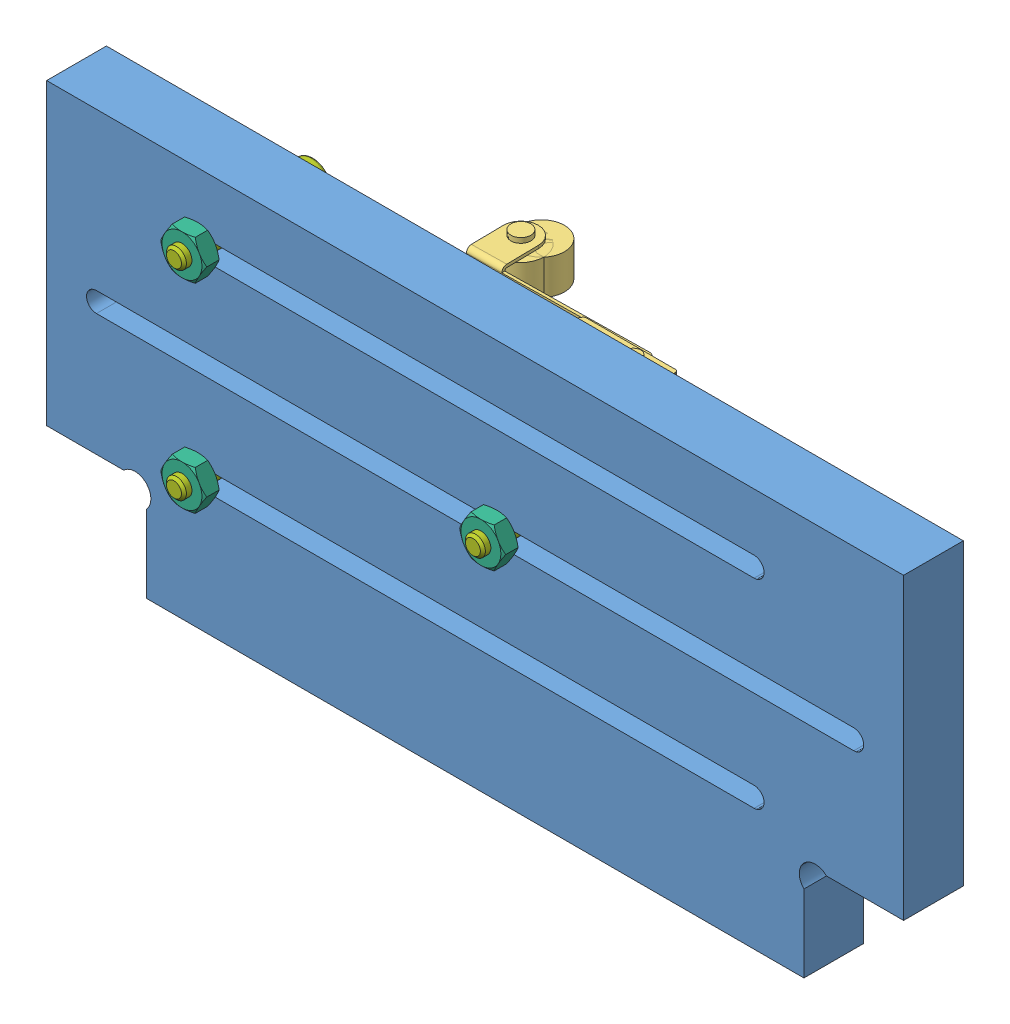
SolidWorks assembly cfc_ferme, configuration Défaut. Lengths in mm.
Overall size (86 40 30.8).
14 component instances, 7 part files, 27 mates.
Components (placement in the parent):
- cfc-platine-1: cfc-platine [Défaut] at (140.8628 -70 0) x (0 0 1) z (0 -1 0) size (6 86 40)
- Grove microswitch v1.0-1: Grove microswitch v1.0 [Défaut] at (-58.8307 23.25 -3.344) x (1 0 0) z (0 1 0) size (41.8 22.4 23.6)
  - PCB grove 20x40-1: PCB grove 20x40 [Défaut] at (-1.988 -1.344 0) size (41.8 1.6 23.6)
  - microswitch 10T85-1: microswitch 10T85 [Défaut] at (9.562 0.256 0) size (22.48 22.4 6.4)
  - Connecteur Grove (coudé CMS)-1: Connecteur Grove (coudé CMS) [Défaut] at (-21.488 0.256 0) x (0 0 -1) z (0 1 0) size (12 10 5)
- entretoise-grove-1: entretoise-grove [Défaut] at (-40.8187 23.25 -2) x (1 0.000242 0) z (0 0 1) size (4 4 2)
- entretoise-grove-2: entretoise-grove [Défaut] at (-70.8187 13.25 -2) size (4 4 2)
- entretoise-grove-3: entretoise-grove [Défaut] at (-70.8187 33.25 -2) size (4 4 2)
- ecrou-h-1: ecrou-h [6007 HU M2] at (-40.8187 23.25 7.6) x (0.866025 -0.5 0) z (-0.5 -0.866025 0) size (4 1.6 4.62)
- ecrou-h-2: ecrou-h [6007 HU M2] at (-70.8187 13.25 7.6) x (0.866025 0.5 0) z (0.5 -0.866025 0) size (4 1.6 4.62)
- ecrou-h-3: ecrou-h [6007 HU M2] at (-70.8187 33.25 7.6) x (-0.866025 0.5 0) z (0.5 0.866025 0) size (4 1.6 4.62)
- vis-chc-1: vis-chc [Vis CHC M2x12] at (-70.8187 13.25 -3.6) x (1 0 0) z (0 1 0) size (3.8 14 3.8)
- vis-chc-2: vis-chc [Vis CHC M2x12] at (-70.8187 33.25 -3.6) x (1 0 0) z (0 1 0) size (3.8 14 3.8)
- vis-chc-3: vis-chc [Vis CHC M2x12] at (-40.8187 23.25 -3.6) x (0.997694 0.067868 0) z (-0.067868 0.997694 0) size (3.8 14 3.8)
Mates (geometry in assembly coordinates):
- Coïncidente1: coincident anti-aligned: plane of cfc-platine-1 through (-8.8686 8.8686 0) normal (0 0 -1)
- Coïncidente2: coincident anti-aligned: plane of cfc-platine-1 through (-10 0 6) normal (0 -1 0)
- Coaxiale1: concentric anti-aligned: cylinder of Grove microswitch v1.0-1/PCB grove 20x40-1 through (-70.8187 33.25 -3.6) axis (0 0 1) radius 1.1; cylinder of entretoise-grove-3 through (-70.8187 33.25 0) axis (0 0 -1) radius 1.2
- Coïncidente4: coincident anti-aligned: plane of Grove microswitch v1.0-1/PCB grove 20x40-1 through (-60.8187 23.25 -2) normal (0 0 1); plane of entretoise-grove-3 through (-70.8187 33.25 -2) normal (0 0 -1)
- Coaxiale2: concentric anti-aligned: cylinder of Grove microswitch v1.0-1/PCB grove 20x40-1 through (-40.8187 23.25 -3.6) axis (0 0 1) radius 1.1; cylinder of entretoise-grove-1 through (-40.8187 23.25 0) axis (0 0 -1) radius 1.2
- Coïncidente5: coincident anti-aligned: plane of Grove microswitch v1.0-1/PCB grove 20x40-1 through (-60.8187 23.25 -2) normal (0 0 1); plane of entretoise-grove-1 through (-40.8187 23.25 -2) normal (0 0 -1)
- Coaxiale3: concentric anti-aligned: cylinder of Grove microswitch v1.0-1/PCB grove 20x40-1 through (-70.8187 13.25 -3.6) axis (0 0 1) radius 1.1; cylinder of entretoise-grove-2 through (-70.8187 13.25 0) axis (0 0 -1) radius 1.2
- Coïncidente6: coincident anti-aligned: plane of Grove microswitch v1.0-1/PCB grove 20x40-1 through (-60.8187 23.25 -2) normal (0 0 1); plane of entretoise-grove-2 through (-70.8187 13.25 -2) normal (0 0 -1)
- Coïncidente7: coincident anti-aligned: plane of cfc-platine-1 through (-8.8686 8.8686 0) normal (0 0 -1); plane of entretoise-grove-1 through (-40.8187 23.25 0) normal (0 0 1)
- Parallèle4: parallel anti-aligned: plane of cfc-platine-1 through (-86 40 6) normal (-1 0 0); plane of Grove microswitch v1.0-1/PCB grove 20x40-1 through (-40.8187 23.25 -3.6) normal (1 0 0)
- Parallèle3: parallel anti-aligned: plane of cfc-platine-1 through (-10 0 6) normal (0 -1 0); plane of Grove microswitch v1.0-1/PCB grove 20x40-1 through (-60.8187 33.25 -3.6) normal (0 1 0)
- Coaxiale4: concentric anti-aligned: cylinder of Grove microswitch v1.0-1/PCB grove 20x40-1 through (-70.8187 13.25 -3.6) axis (0 0 1) radius 1.1; cylinder of vis-chc-1 through (-70.8187 13.25 8.4) axis (0 0 -1) radius 1
- Coaxiale5: concentric anti-aligned: cylinder of Grove microswitch v1.0-1/PCB grove 20x40-1 through (-40.8187 23.25 -3.6) axis (0 0 1) radius 1.1; cylinder of vis-chc-3 through (-40.8187 23.25 8.4) axis (0 0 -1) radius 1
- Coaxiale6: concentric anti-aligned: cylinder of Grove microswitch v1.0-1/PCB grove 20x40-1 through (-70.8187 33.25 -3.6) axis (0 0 1) radius 1.1; cylinder of vis-chc-2 through (-70.8187 33.25 8.4) axis (0 0 -1) radius 1
- Coïncidente11: coincident anti-aligned: plane of Grove microswitch v1.0-1/PCB grove 20x40-1 through (-60.8187 23.25 -3.6) normal (0 0 -1); plane of vis-chc-3 through (-40.8187 23.25 -3.6) normal (0 0 1)
- Coïncidente12: coincident anti-aligned: plane of Grove microswitch v1.0-1/PCB grove 20x40-1 through (-60.8187 23.25 -3.6) normal (0 0 -1); plane of vis-chc-2 through (-70.8187 33.25 -3.6) normal (0 0 1)
- Coïncidente13: coincident anti-aligned: plane of Grove microswitch v1.0-1/PCB grove 20x40-1 through (-60.8187 23.25 -3.6) normal (0 0 -1); plane of vis-chc-1 through (-70.8187 13.25 -3.6) normal (0 0 1)
- Coaxiale7: concentric anti-aligned: cylinder of ecrou-h-2 through (-70.8187 13.25 6) axis (0 0 1) radius 0.7835; cylinder of vis-chc-1 through (-70.8187 13.25 8.4) axis (0 0 -1) radius 1
- Coaxiale8: concentric anti-aligned: cylinder of ecrou-h-3 through (-70.8187 33.25 6) axis (0 0 1) radius 0.7835; cylinder of vis-chc-2 through (-70.8187 33.25 8.4) axis (0 0 -1) radius 1
- Coaxiale9: concentric anti-aligned: cylinder of ecrou-h-1 through (-40.8187 23.25 6) axis (0 0 1) radius 0.7835; cylinder of vis-chc-3 through (-40.8187 23.25 8.4) axis (0 0 -1) radius 1
- Coïncidente14: coincident anti-aligned: plane of cfc-platine-1 through (-8.8686 8.8686 6) normal (0 0 1); plane of ecrou-h-2 through (-69.664 15.25 6) normal (0 0 -1)
- Coïncidente15: coincident anti-aligned: plane of cfc-platine-1 through (-8.8686 8.8686 6) normal (0 0 1); plane of ecrou-h-1 through (-38.5093 23.25 6) normal (0 0 -1)
- Coïncidente16: coincident anti-aligned: plane of cfc-platine-1 through (-8.8686 8.8686 6) normal (0 0 1); plane of ecrou-h-3 through (-73.1281 33.25 6) normal (0 0 -1)
- Parallèle5: parallel aligned: plane of cfc-platine-1 through (0 40 6) normal (0 1 0); plane of ecrou-h-2 through (-69.664 15.25 6) normal (0 1 0)
- Parallèle6: parallel aligned: plane of ecrou-h-1 through (-39.664 25.25 6) normal (0 1 0); plane of ecrou-h-2 through (-69.664 15.25 6) normal (0 1 0)
- Parallèle7: parallel aligned: plane of ecrou-h-2 through (-69.664 15.25 6) normal (0 1 0); plane of ecrou-h-3 through (-69.664 35.25 6) normal (0 1 0)
- Tangent1: tangent anti-aligned: plane of cfc-platine-1 through (-5 22.25 6) normal (0 1 0); cylinder of vis-chc-3 through (-40.8187 23.25 8.4) axis (0 0 -1) radius 1
